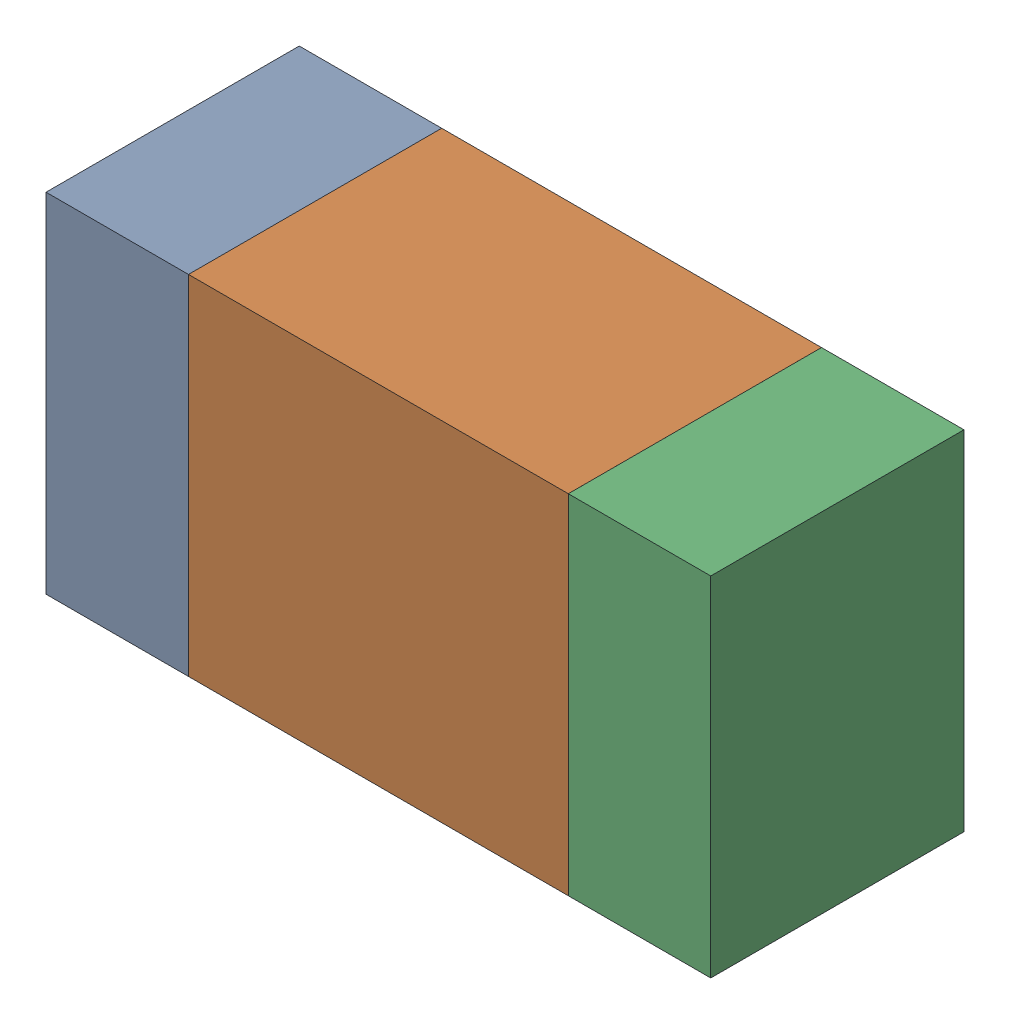
SolidWorks assembly R502_2PCB, configuration Default. Lengths in mm.
Overall size (1.05 0.55 0.4).
6 component instances, 2 part files, 0 mates.
Components (placement in the parent):
- 854785432-1: 854785432 [Default] at (156.0628 89.2681 0) size (0.22 0.55 0.4)
  - Extruded-1: Extruded [Default] at origin size (0.22 0.55 0.4)
- 854785568-1: 854785568 [Default] at (156.4753 89.2681 0) size (0.6 0.55 0.4)
  - Extruded_2-1: Extruded_2 [Default] at origin size (0.6 0.55 0.4)
- 854785432-2: 854785432 [Default] at (156.8878 89.2681 0) size (0.22 0.55 0.4)
  - Extruded-1: Extruded [Default] at origin size (0.22 0.55 0.4)
